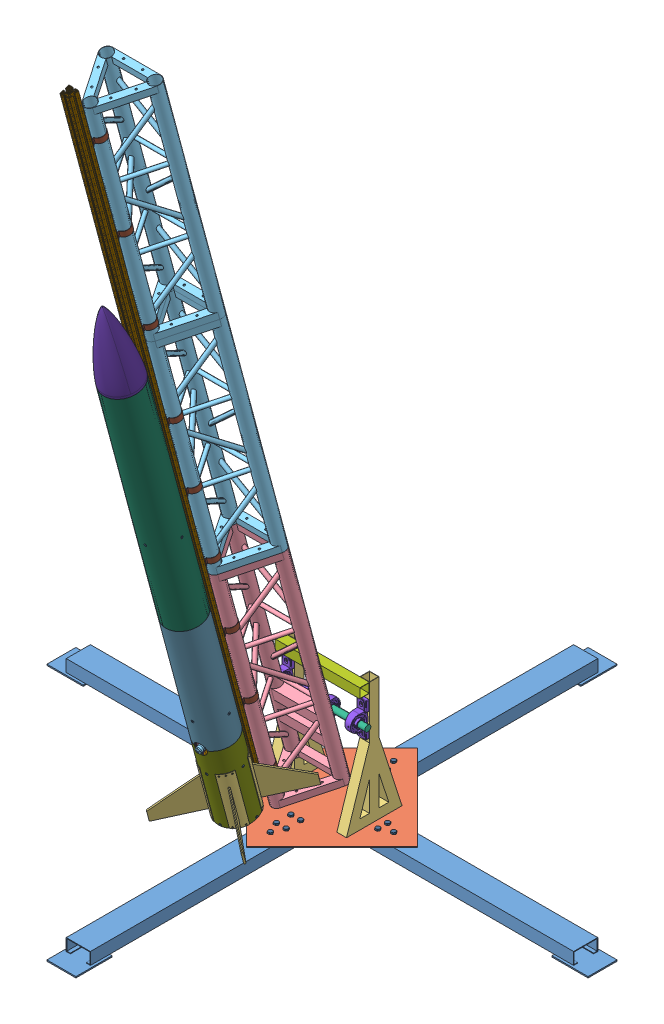
SolidWorks assembly Montagem_Diogo, configuration Default. Lengths in mm.
Overall size (2240 3135.17 2432.37).
172 component instances, 59 part files, 0 mates.
Components (placement in the parent):
- Pernas_Base_v2_Valor predeterminado-1: Pernas_Base_v2_Valor predeterminado [Default] at (-52.0403 -29.4954 1070) size (120 55 1070)
- Pernas_Base_v2_Valor predeterminado-2: Pernas_Base_v2_Valor predeterminado [Default] at (47.9597 -29.4954 1070) x (0 0 -1) z (1 0 0) size (120 55 1070)
- Pernas_Base_v2_Valor predeterminado-3: Pernas_Base_v2_Valor predeterminado [Default] at (-52.0403 -29.4954 970) x (0 0 1) z (-1 0 0) size (120 55 1070)
- Pernas_Base_v2_Valor predeterminado-4: Pernas_Base_v2_Valor predeterminado [Default] at (47.9597 -29.4954 970) x (-1 0 0) z (0 0 -1) size (120 55 1070)
- Base_v2_Valor predeterminado-1: Base_v2_Valor predeterminado [Default] at (280.8024 20.5046 1020) x (-0.707107 0 -0.707107) z (0 1 0) size (500 500 2.65)
- Haste_Valor predeterminado-1: Haste_Valor predeterminado [Default] at (172.9597 23.1546 1000) x (-1 0 0) z (0 0 -1) size (40 510 230)
- Haste_Valor predeterminado-2: Haste_Valor predeterminado [Default] at (-177.0403 23.1546 1040) size (40 510 230)
- Treliça-v3-mod-1: Treliça-v3-mod [Default] at (97.9597 162.3507 1076.7624) x (-0.5 0.224144 -0.836516) z (0.866025 0.12941 -0.482963) size (250.8 1000 224.01)
- Treliça-v2-mod-1: Treliça-v2-mod [Default] at (-2.0403 1083.4478 1502.8847) x (1 0 0) z (0 -0.258819 0.965926) size (250.8 1000 224.01)
- Treliça-v2-mod-2: Treliça-v2-mod [Default] at (-2.0403 2049.3736 1761.7038) x (1 0 0) z (0 -0.258819 0.965926) size (250.8 1000 224.01)
- Pino_1_pol_Valor predeterminado-1: Pino_1_pol_Valor predeterminado [Default] at (-197.3723 400.5345 1076.5) x (0 -0.908025 0.418916) z (1 0 0) size (25 25 400)
- Trava_Valor predeterminado-1: Trava_Valor predeterminado [Default] at (-177.0403 493.1546 1080) x (0 0 -1) z (1 0 0) size (40 40 350)
- ucp205-1: ucp205 [Default] at (152.9597 400.5345 1076.5) size (38.8 140 71.62)
- ucp205-2: ucp205 [Default] at (-157.0403 400.5345 1076.5) size (38.8 140 71.62)
- ucp205-3: ucp205 [Default] at (-48.0403 400.5345 1076.5) x (-1 0 0) z (0 0.258819 -0.965926) size (38.8 140 71.62)
- ucp205-4: ucp205 [Default] at (43.9597 400.5345 1076.5) x (-1 0 0) z (0 0.258819 -0.965926) size (38.8 140 71.62)
- perfil_40x40_Valor predeterminado_Como usinado_-1: perfil_40x40_Valor predeterminado_Como usinado_ [Default] at (-2.0403 1646.6109 1719.3533) x (1 0 0) z (0 -0.965926 -0.258819) size (40 40 3000)
- Parafuso_M_10_30mm_pols_91310A630-1: Parafuso_M_10_30mm_pols_91310A630 [Default] at (-2.0403 11.3546 1275) x (0 -1 0) z (0 0 1) size (36.4 19.63 17)
- Parafuso_M_10_30mm_pols_91310A630-2: Parafuso_M_10_30mm_pols_91310A630 [Default] at (-22.0403 11.3546 1170) x (0 -1 0) z (0 0 1) size (36.4 19.63 17)
- Parafuso_M_10_30mm_pols_91310A630-3: Parafuso_M_10_30mm_pols_91310A630 [Default] at (-22.0403 11.3546 1230) x (0 -1 0) z (0 0 1) size (36.4 19.63 17)
- Parafuso_M_10_30mm_pols_91310A630-4: Parafuso_M_10_30mm_pols_91310A630 [Default] at (17.9597 11.3546 1170) x (0 -1 0) z (0 0 1) size (36.4 19.63 17)
- Parafuso_M_10_30mm_pols_91310A630-5: Parafuso_M_10_30mm_pols_91310A630 [Default] at (17.9597 11.3546 1230) x (0 -1 0) z (-0.102079 0 0.994776) size (36.4 19.63 17)
- Parafuso_M_10_30mm_pols_91310A630-6: Parafuso_M_10_30mm_pols_91310A630 [Default] at (-2.0403 11.3546 765) x (0 -1 0) z (0 0 1) size (36.4 19.63 17)
- Parafuso_M_10_30mm_pols_91310A630-7: Parafuso_M_10_30mm_pols_91310A630 [Default] at (-22.0403 11.3546 870) x (0 -1 0) z (0 0 1) size (36.4 19.63 17)
- Parafuso_M_10_30mm_pols_91310A630-8: Parafuso_M_10_30mm_pols_91310A630 [Default] at (-22.0403 11.3546 810) x (0 -1 0) z (0 0 1) size (36.4 19.63 17)
- Parafuso_M_10_30mm_pols_91310A630-9: Parafuso_M_10_30mm_pols_91310A630 [Default] at (17.9597 11.3546 870) x (0 -1 0) z (0 0 1) size (36.4 19.63 17)
- Parafuso_M_10_30mm_pols_91310A630-10: Parafuso_M_10_30mm_pols_91310A630 [Default] at (17.9597 11.3546 810) x (0 -1 0) z (0.102079 0 0.994776) size (36.4 19.63 17)
- Parafuso_M_10_30mm_pols_91310A630-11: Parafuso_M_10_30mm_pols_91310A630 [Default] at (-257.0403 11.3546 1020) x (0 -1 0) z (-0.888061 0 0.459726) size (36.4 19.63 17)
- Parafuso_M_10_30mm_pols_91310A630-12: Parafuso_M_10_30mm_pols_91310A630 [Default] at (-212.0403 11.3546 1040) x (0 -1 0) z (-0.888061 0 0.459726) size (36.4 19.63 17)
- Parafuso_M_10_30mm_pols_91310A630-13: Parafuso_M_10_30mm_pols_91310A630 [Default] at (-212.0403 11.3546 1000) x (0 -1 0) z (-0.888061 0 0.459726) size (36.4 19.63 17)
- Parafuso_M_10_30mm_pols_91310A630-14: Parafuso_M_10_30mm_pols_91310A630 [Default] at (252.9597 11.3546 1020) x (0 -1 0) z (-0.888061 0 -0.459726) size (36.4 19.63 17)
- Parafuso_M_10_30mm_pols_91310A630-15: Parafuso_M_10_30mm_pols_91310A630 [Default] at (207.9597 11.3546 1040) x (0 -1 0) z (-0.888061 0 -0.459726) size (36.4 19.63 17)
- Parafuso_M_10_30mm_pols_91310A630-16: Parafuso_M_10_30mm_pols_91310A630 [Default] at (207.9597 11.3546 1000) x (0 -1 0) z (-0.888061 0 -0.459726) size (36.4 19.63 17)
- abraçadeira_2in-1: abraçadeira_2in [Default] at (-2.0403 251.1948 1324.7472) x (1 0 0) z (0 0.965926 0.258819) size (53.2 69.94 24)
- abraçadeira_2in-2: abraçadeira_2in [Default] at (-2.0403 540.9726 1402.3929) x (1 0 0) z (0 0.965926 0.258819) size (53.2 69.94 24)
- abraçadeira_2in-3: abraçadeira_2in [Default] at (-2.0403 830.7503 1480.0386) x (1 0 0) z (0 0.965926 0.258819) size (53.2 69.94 24)
- abraçadeira_2in-4: abraçadeira_2in [Default] at (-2.0403 1120.5281 1557.6843) x (1 0 0) z (0 0.965926 0.258819) size (53.2 69.94 24)
- abraçadeira_2in-5: abraçadeira_2in [Default] at (-2.0403 1410.3058 1635.33) x (1 0 0) z (0 0.965926 0.258819) size (53.2 69.94 24)
- abraçadeira_2in-6: abraçadeira_2in [Default] at (-2.0403 1700.0836 1712.9758) x (1 0 0) z (0 0.965926 0.258819) size (53.2 69.94 24)
- abraçadeira_2in-7: abraçadeira_2in [Default] at (-2.0403 2086.4539 1816.5034) x (1 0 0) z (0 0.965926 0.258819) size (53.2 69.94 24)
- abraçadeira_2in-8: abraçadeira_2in [Default] at (-2.0403 2472.8242 1920.031) x (1 0 0) z (0 0.965926 0.258819) size (53.2 69.94 24)
- abraçadeira_2in-9: abraçadeira_2in [Default] at (-2.0403 2859.1945 2023.5586) x (1 0 0) z (0 0.965926 0.258819) size (53.2 69.94 24)
- porca_martelo_M6-1: porca_martelo_M6 [Default] at (-2.0403 2868.5857 2034.8748) x (0 0.965926 0.258819) z (-1 0 0) size (7.7 6 16)
- DDLS_II_v05_LASC_Valor predeterminado-1: DDLS_II_v05_LASC_Valor predeterminado [Default] at (8.8764 189.1016 1425.0956) x (-0.773658 0.163989 -0.612014) z (0.633604 0.200237 -0.747296) size (514 2164.68 514)
  - fuselagem_v04_Valor predeterminado-1: fuselagem_v04_Valor predeterminado [Default] x (-0.707107 0 -0.707107) z (0.707107 0 -0.707107) size (210.6 2155.68 210.6)
    - pescoco_valvula_26102020_1025_Valor predeterminado-1: pescoco_valvula_26102020_1025_Valor predeterminado [Default] at (0 330 0) size (145.71 150 150)
    - tubo2_17022020_1025_Valor predeterminado-1: tubo2_17022020_1025_Valor predeterminado [Default] at (0 330 0) size (155 514.53 155)
    - tubo3_17022020_1025_Valor predeterminado-1: tubo3_17022020_1025_Valor predeterminado [Default] at (0 843 0) size (155 1044.68 155)
    - tubo1_17022020_1025_Valor predeterminado-1: tubo1_17022020_1025_Valor predeterminado [Default] at origin size (155 331.53 155)
    - DDLSII_Coifa_VonKarman_v1_Valor predeterminado-1: DDLSII_Coifa_VonKarman_v1_Valor predeterminado [Default] at (0 2155.68 0) x (0 -1 0) z (0.503622 0 -0.863924) size (468 154 154)
  - DIN 912 - M6 x 1 x 25_Valor predeterminado-1: DIN 912 - M6 x 1 x 25_Valor predeterminado [Default] at (74.3 6 0) x (-1 0 0) z (0 0.043133 -0.999069) size (31 10 10)
  - DIN 7991 - M5 x 0.8 x 10_Valor predeterminado-1: DIN 7991 - M5 x 0.8 x 10_Valor predeterminado [Default] at (-54.9873 6 54.9873) x (0.707107 0 -0.707107) z (0.691467 0.209156 0.691467) size (10 9.64 9.64)
  - DIN 912 - M5 x 0.8 x 10_Valor predeterminado-1: DIN 912 - M5 x 0.8 x 10_Valor predeterminado [Default] at (0 818 -73.3) x (0 0 1) z (-0.394606 -0.918851 0) size (15 8.5 8.5)
  - DIN 912 - M5 x 0.8 x 10_Valor predeterminado-2: DIN 912 - M5 x 0.8 x 10_Valor predeterminado [Default] at (-73.3 818 0) x (1 0 0) z (0 -0.98779 -0.155794) size (15 8.5 8.5)
  - DIN 912 - M6 x 1 x 25_Valor predeterminado-2: DIN 912 - M6 x 1 x 25_Valor predeterminado [Default] at (0 223 74.3) x (0 0 -1) z (0.737606 0.675231 0) size (31 10 10)
  - DIN 912 - M6 x 1 x 25_Valor predeterminado-3: DIN 912 - M6 x 1 x 25_Valor predeterminado [Default] at (-74.3 223 0) x (1 0 0) z (0 -0.737606 0.675231) size (31 10 10)
  - DDLSII_Aleta_Trapeizodal_v1_Valor predeterminado-1: DDLSII_Aleta_Trapeizodal_v1_Valor predeterminado [Default] at (0 26.4771 77) x (0 1 0) z (0 0 1) size (231.48 60.46 185.86)
  - DIN 912 - M6 x 1 x 25_Valor predeterminado-4: DIN 912 - M6 x 1 x 25_Valor predeterminado [Default] at (0 6 -74.3) x (0 0 1) z (-0.999069 0.043133 0) size (31 10 10)
  - DIN 912 - M6 x 1 x 25_Valor predeterminado-5: DIN 912 - M6 x 1 x 25_Valor predeterminado [Default] at (0 6 74.3) x (0 0 -1) z (0.924066 0.382233 0) size (31 10 10)
  - DDLSII_Aleta_Trapeizodal_v1_Valor predeterminado-2: DDLSII_Aleta_Trapeizodal_v1_Valor predeterminado [Default] at (-77 26.4771 0) x (0 1 0) z (-1 0 0) size (231.48 60.46 185.86)
  - DIN 912 - M6 x 1 x 25_Valor predeterminado-6: DIN 912 - M6 x 1 x 25_Valor predeterminado [Default] at (74.3 223 0) x (-1 0 0) z (0 0.200992 -0.979593) size (31 10 10)
  - DIN 912 - M5 x 0.8 x 10_Valor predeterminado-3: DIN 912 - M5 x 0.8 x 10_Valor predeterminado [Default] at (73.3 448 0) x (-1 0 0) z (0 0.09878 0.995109) size (15 8.5 8.5)
  - DIN 912 - M5 x 0.8 x 10_Valor predeterminado-4: DIN 912 - M5 x 0.8 x 10_Valor predeterminado [Default] at (0 818 73.3) x (0 0 -1) z (-0.728474 -0.685073 0) size (15 8.5 8.5)
  - DIN 912 - M5 x 0.8 x 10_Valor predeterminado-5: DIN 912 - M5 x 0.8 x 10_Valor predeterminado [Default] at (73.3 818 0) x (-1 0 0) z (0 -0.918851 -0.394606) size (15 8.5 8.5)
  - DIN 912 - M6 x 1 x 25_Valor predeterminado-7: DIN 912 - M6 x 1 x 25_Valor predeterminado [Default] at (-74.3 6 0) x (1 0 0) z (0 -0.843653 0.536889) size (31 10 10)
  - DIN 912 - M5 x 0.8 x 10_Valor predeterminado-6: DIN 912 - M5 x 0.8 x 10_Valor predeterminado [Default] at (-73.3 448 0) x (1 0 0) z (0 0.968882 -0.247524) size (15 8.5 8.5)
  - DIN 912 - M5 x 0.8 x 10_Valor predeterminado-7: DIN 912 - M5 x 0.8 x 10_Valor predeterminado [Default] at (0 448 -73.3) x (0 0 1) z (0.995109 0.09878 0) size (15 8.5 8.5)
  - DIN 7991 - M5 x 0.8 x 10_Valor predeterminado-2: DIN 7991 - M5 x 0.8 x 10_Valor predeterminado [Default] at (54.9873 6 54.9873) x (-0.707107 0 -0.707107) z (0.461185 -0.758034 -0.461185) size (10 9.64 9.64)
  - DIN 912 - M5 x 0.8 x 10_Valor predeterminado-8: DIN 912 - M5 x 0.8 x 10_Valor predeterminado [Default] at (0 448 73.3) x (0 0 -1) z (-0.968882 -0.247524 0) size (15 8.5 8.5)
  - DIN 7991 - M5 x 0.8 x 10_Valor predeterminado-3: DIN 7991 - M5 x 0.8 x 10_Valor predeterminado [Default] at (54.9873 223 54.9873) x (-0.707107 0 -0.707107) z (0.569024 -0.593652 -0.569024) size (10 9.64 9.64)
  - DDLSII_Aleta_Trapeizodal_v1_Valor predeterminado-3: DDLSII_Aleta_Trapeizodal_v1_Valor predeterminado [Default] at (77 26.4771 0) x (0 1 0) z (1 0 0) size (231.48 60.46 185.86)
  - DIN 7991 - M5 x 0.8 x 10_Valor predeterminado-4: DIN 7991 - M5 x 0.8 x 10_Valor predeterminado [Default] at (54.9873 448 54.9873) x (-0.707107 0 -0.707107) z (0.634453 -0.441518 -0.634453) size (10 9.64 9.64)
  - DIN 7991 - M5 x 0.8 x 10_Valor predeterminado-5: DIN 7991 - M5 x 0.8 x 10_Valor predeterminado [Default] at (54.9873 1204 54.9873) x (-0.707107 0 -0.707107) z (0.669219 -0.322942 -0.669219) size (10 9.64 9.64)
  - DIN 912 - M6 x 1 x 25_Valor predeterminado-8: DIN 912 - M6 x 1 x 25_Valor predeterminado [Default] at (0 223 -74.3) x (0 0 1) z (-0.999069 0.043133 0) size (31 10 10)
  - Paraquedas_Valor predeterminado-1: Paraquedas_Valor predeterminado [Default] at (0 1268.1902 0) x (-0.508851 0 0.860854) z (-0.860854 0 -0.508851) size (142 500 142)
  - DIN 7991 - M5 x 0.8 x 20_Valor predeterminado-1: DIN 7991 - M5 x 0.8 x 20_Valor predeterminado [Default] at (-30 1189.5 -51.9615) x (0 1 0) z (-0.631711 0 -0.775204) size (20 9.64 9.64)
  - DIN 7991 - M5 x 0.8 x 20_Valor predeterminado-2: DIN 7991 - M5 x 0.8 x 20_Valor predeterminado [Default] at (51.9615 1189.5 -30) x (0 1 0) z (-0.227827 0 -0.973702) size (20 9.64 9.64)
  - 90592A022_STEEL HEX NUT_90592A022-1: 90592A022_STEEL HEX NUT_90592A022 [Default] at (0 1857.73 0) size (13 6.97 15.01)
  - DIN 7991 - M5 x 0.8 x 10_Valor predeterminado-6: DIN 7991 - M5 x 0.8 x 10_Valor predeterminado [Default] at (54.9873 6 -54.9873) x (-0.707107 0 0.707107) z (-0.265712 -0.926712 -0.265712) size (10 9.64 9.64)
  - DIN 7991 - M5 x 0.8 x 10_Valor predeterminado-7: DIN 7991 - M5 x 0.8 x 10_Valor predeterminado [Default] at (54.9873 223 -54.9873) x (-0.707107 0 0.707107) z (-0.223229 -0.948861 -0.223229) size (10 9.64 9.64)
  - DIN 7991 - M5 x 0.8 x 20_Valor predeterminado-3: DIN 7991 - M5 x 0.8 x 20_Valor predeterminado [Default] at (30 1189.5 51.9615) x (0 1 0) z (-0.040246 0 -0.99919) size (20 9.64 9.64)
  - DIN 7991 - M5 x 0.8 x 10_Valor predeterminado-8: DIN 7991 - M5 x 0.8 x 10_Valor predeterminado [Default] at (-54.9873 1204 -54.9873) x (0.707107 0 0.707107) z (-0.461185 -0.758034 0.461185) size (10 9.64 9.64)
  - Assembly_Completo_LASC_sem_antiretorno_Valor predeterminado-1: Assembly_Completo_LASC_sem_antiretorno_Valor predeterminado [Default] at (-564.4867 231.8653 423.7249) x (0 -1 0) z (0.707107 0 -0.707107) size (872.4 212.33 212.33)
    - Assembly_Motor_8_1_Valor predeterminado-1: Assembly_Motor_8_1_Valor predeterminado [Default] at (5.6555 -208.983 804.3704) x (0 0.699248 0.714879) z (0 0.714879 -0.699248) size (150.15 268 150.15)
      - Parafuso M6_Valor predeterminado-1: Parafuso M6_Valor predeterminado [Default] at (29.0923 3.2098 201.9329) x (-0.871499 0 0.490397) z (-0.490397 0 -0.871499) size (8 8 20.2)
      - Casing (1)_Valor predeterminado-1: Casing (1)_Valor predeterminado [Default] at (1.0416 -11.7902 152.0832) x (0.999902 0 0.014033) z (-0.014033 0 0.999902) size (114.4 247 114.4)
      - Parafuso M6_Valor predeterminado-2: Parafuso M6_Valor predeterminado [Default] at (-27.0091 3.2098 102.2334) x (0.871499 0 -0.490397) z (0.490397 0 0.871499) size (8 8 20.2)
      - Parafuso M6_Valor predeterminado-3: Parafuso M6_Valor predeterminado [Default] at (-48.8082 220.2098 180.1339) x (-0.490397 0 -0.871499) z (0.871499 0 -0.490397) size (8 8 20.2)
      - Parafuso M6_Valor predeterminado-4: Parafuso M6_Valor predeterminado [Default] at (50.8913 3.2098 124.0324) x (0.490397 0 0.871499) z (-0.871499 0 0.490397) size (8 8 20.2)
      - Parafuso M6_Valor predeterminado-5: Parafuso M6_Valor predeterminado [Default] at (-48.8082 3.2098 180.1339) x (-0.490397 0 -0.871499) z (0.871499 0 -0.490397) size (8 8 20.2)
      - Parafuso M6_Valor predeterminado-6: Parafuso M6_Valor predeterminado [Default] at (29.0923 220.2098 201.9329) x (-0.871499 0 0.490397) z (-0.490397 0 -0.871499) size (8 8 20.2)
      - Parafuso M6_Valor predeterminado-7: Parafuso M6_Valor predeterminado [Default] at (30.1874 3.2098 102.8657) x (0.860446 0 0.509542) z (-0.509542 0 0.860446) size (8 8 20.2)
      - Parafuso M6_Valor predeterminado-8: Parafuso M6_Valor predeterminado [Default] at (50.2591 3.2098 181.2289) x (-0.509542 0 0.860446) z (-0.860446 0 -0.509542) size (8 8 20.2)
      - Parafuso M6_Valor predeterminado-9: Parafuso M6_Valor predeterminado [Default] at (-48.8082 220.2098 180.1339) x (-0.490397 0 -0.871499) z (0.871499 0 -0.490397) size (8 8 20.2)
      - Parafuso M6_Valor predeterminado-10: Parafuso M6_Valor predeterminado [Default] at (30.1874 3.2098 102.8657) x (0.860446 0 0.509542) z (-0.509542 0 0.860446) size (8 8 20.2)
      - Parafuso M6_Valor predeterminado-11: Parafuso M6_Valor predeterminado [Default] at (50.8913 3.2098 124.0324) x (0.490397 0 0.871499) z (-0.871499 0 0.490397) size (8 8 20.2)
      - Parafuso M6_Valor predeterminado-12: Parafuso M6_Valor predeterminado [Default] at (-48.1759 3.2098 122.9374) x (0.509542 0 -0.860446) z (0.860446 0 0.509542) size (8 8 20.2)
      - Parafuso M6_Valor predeterminado-13: Parafuso M6_Valor predeterminado [Default] at (-48.1759 3.2098 122.9374) x (0.509542 0 -0.860446) z (0.860446 0 0.509542) size (8 8 20.2)
      - Parafuso M6_Valor predeterminado-14: Parafuso M6_Valor predeterminado [Default] at (29.0923 3.2098 201.9329) x (-0.871499 0 0.490397) z (-0.490397 0 -0.871499) size (8 8 20.2)
      - Parafuso M6_Valor predeterminado-15: Parafuso M6_Valor predeterminado [Default] at (-27.0091 3.2098 102.2334) x (0.871499 0 -0.490397) z (0.490397 0 0.871499) size (8 8 20.2)
      - Parafuso M6_Valor predeterminado-16: Parafuso M6_Valor predeterminado [Default] at (-27.0091 220.2098 102.2334) x (0.871499 0 -0.490397) z (0.490397 0 0.871499) size (8 8 20.2)
      - Parafuso M6_Valor predeterminado-17: Parafuso M6_Valor predeterminado [Default] at (50.2591 220.2098 181.2289) x (-0.509542 0 0.860446) z (-0.860446 0 -0.509542) size (8 8 20.2)
      - Parafuso M6_Valor predeterminado-18: Parafuso M6_Valor predeterminado [Default] at (50.8913 220.2098 124.0324) x (0.490397 0 0.871499) z (-0.871499 0 0.490397) size (8 8 20.2)
      - Parafuso M6_Valor predeterminado-19: Parafuso M6_Valor predeterminado [Default] at (-48.1759 220.2098 122.9374) x (0.509542 0 -0.860446) z (0.860446 0 0.509542) size (8 8 20.2)
      - Parafuso M6_Valor predeterminado-20: Parafuso M6_Valor predeterminado [Default] at (-28.1042 3.2098 201.3007) x (-0.860446 0 -0.509542) z (0.509542 0 -0.860446) size (8 8 20.2)
      - Parafuso M6_Valor predeterminado-21: Parafuso M6_Valor predeterminado [Default] at (-48.8082 3.2098 180.1339) x (-0.490397 0 -0.871499) z (0.871499 0 -0.490397) size (8 8 20.2)
      - Parafuso M6_Valor predeterminado-22: Parafuso M6_Valor predeterminado [Default] at (50.2591 3.2098 181.2289) x (-0.509542 0 0.860446) z (-0.860446 0 -0.509542) size (8 8 20.2)
      - Parafuso M6_Valor predeterminado-23: Parafuso M6_Valor predeterminado [Default] at (29.0923 220.2098 201.9329) x (-0.871499 0 0.490397) z (-0.490397 0 -0.871499) size (8 8 20.2)
      - Parafuso M6_Valor predeterminado-24: Parafuso M6_Valor predeterminado [Default] at (-28.1042 3.2098 201.3007) x (-0.860446 0 -0.509542) z (0.509542 0 -0.860446) size (8 8 20.2)
      - injetor_Valor predeterminado-1: injetor_Valor predeterminado [Default] at (1.0416 8.2098 152.0832) x (-0.860446 0 -0.509542) z (-0.509542 0 0.860446) size (109.6 43 109.6)
      - Parafuso M6_Valor predeterminado-25: Parafuso M6_Valor predeterminado [Default] at (-27.0091 220.2098 102.2334) x (0.871499 0 -0.490397) z (0.490397 0 0.871499) size (8 8 20.2)
      - Parafuso M6_Valor predeterminado-26: Parafuso M6_Valor predeterminado [Default] at (30.1874 220.2098 102.8657) x (0.860446 0 0.509542) z (-0.509542 0 0.860446) size (8 8 20.2)
      - Parafuso M6_Valor predeterminado-27: Parafuso M6_Valor predeterminado [Default] at (-48.1759 220.2098 122.9374) x (0.509542 0 -0.860446) z (0.860446 0 0.509542) size (8 8 20.2)
      - placa_injetora_Valor predeterminado-1: placa_injetora_Valor predeterminado [Default] at (1.0416 8.2098 152.0832) x (-0.860446 0 -0.509542) z (0 -1 0) size (90 90 12)
      - Grao_DDLS_2_Peca_Modificada_8_1_Valor predeterminado-1: Grao_DDLS_2_Peca_Modificada_8_1_Valor predeterminado [Default] at (1.0416 135.1998 152.0832) x (-0.535831 0 -0.844325) z (0 -1 0) size (101.6 101.6 70.19)
      - Montagem_Tubeira_Coupler_8_1_2020_Valor predeterminado-1: Montagem_Tubeira_Coupler_8_1_2020_Valor predeterminado [Default] at (-6.5392 197.5822 154.1075) x (-0.966147 0 0.257991) z (0.257991 0 0.966147) size (109.6 65 109.6)
        - Coupler_DDLS_2_Peca_Modificada_8_1_Valor predeterminado-1: Coupler_DDLS_2_Peca_Modificada_8_1_Valor predeterminado [Default] at (-7.8464 -7.1276 0) size (109.6 65 109.6)
        - Tubeira_DDLS_2_Peca_Modificada_8_1_Valor predeterminado-1: Tubeira_DDLS_2_Peca_Modificada_8_1_Valor predeterminado [Default] at (-7.8464 4.2977 0) size (93.6 65 93.6)
      - Parafuso M6_Valor predeterminado-28: Parafuso M6_Valor predeterminado [Default] at (50.2591 220.2098 181.2289) x (-0.509542 0 0.860446) z (-0.860446 0 -0.509542) size (8 8 20.2)
      - Parafuso M6_Valor predeterminado-29: Parafuso M6_Valor predeterminado [Default] at (-28.1042 220.2098 201.3007) x (-0.860446 0 -0.509542) z (0.509542 0 -0.860446) size (8 8 20.2)
      - Parafuso M6_Valor predeterminado-30: Parafuso M6_Valor predeterminado [Default] at (30.1874 220.2098 102.8657) x (0.860446 0 0.509542) z (-0.509542 0 0.860446) size (8 8 20.2)
      - Parafuso M6_Valor predeterminado-31: Parafuso M6_Valor predeterminado [Default] at (50.8913 220.2098 124.0324) x (0.490397 0 0.871499) z (-0.871499 0 0.490397) size (8 8 20.2)
      - Parafuso M6_Valor predeterminado-32: Parafuso M6_Valor predeterminado [Default] at (-28.1042 220.2098 201.3007) x (-0.860446 0 -0.509542) z (0.509542 0 -0.860446) size (8 8 20.2)
    - T-1.2_3.4_1.2_NPT_MACHO_Valor predeterminado-1: T-1.2_3.4_1.2_NPT_MACHO_Valor predeterminado [Default] at (-98.5347 -99.5336 698.7712) x (0 0 1) z (-1 0 0) size (26.12 57 82)
    - Montagem_Tanque_Completo_Valor predeterminado-1: Montagem_Tanque_Completo_Valor predeterminado [Default] at (-384.0347 -108.7807 655.6336) x (0 -0.209601 -0.977787) z (0 0.977787 -0.209601) size (132.5 465 132.5)
      - TampaInferior_Valor predeterminado-1: TampaInferior_Valor predeterminado [Default] at (-44.1176 -202.8436 0) x (-0.999998 0 -0.002101) z (-0.002101 0 0.999998) size (100 46 100)
      - Tubo_Valor predeterminado-1: Tubo_Valor predeterminado [Default] at (-44.1176 -207.5 0) size (111.1 455 111.1)
      - TampaSuperior_Valor predeterminado-1: TampaSuperior_Valor predeterminado [Default] at (-44.1176 242.8436 0) x (0.415415 0 -0.909632) z (0.909632 0 0.415415) size (100 36 100)
    - Assembly_Conexões_Valor predeterminado-1: Assembly_Conexões_Valor predeterminado [Default] at (-139.5347 -113.07 687.6612) size (476.1 35.34 86.53)
      - valve_solenoide_Valor predeterminado-1: valve_solenoide_Valor predeterminado [Default] at (-28.8974 13.5364 68.8576) x (0 -0.833828 0.552025) z (1 0 0) size (25.5 25.5 61)
      - Montagem1_Valor predeterminado-1: Montagem1_Valor predeterminado [Default] at (-88.5249 15.3016 11.6109) x (0 -1 0) z (1 0 0) size (25.66 57.22 444)
        - connection_Valor predeterminado-1: connection_Valor predeterminado [Default] at (1.7652 0.5009 44.5249) size (25.66 22.22 44.5)
        - tuboexterno_Valor predeterminado-1: tuboexterno_Valor predeterminado [Default] at (1.7652 -45.6091 66.5249) x (1 0 0) z (0 1 0) size (3.17 3.17 35)
        - tubointerno_Valor predeterminado-1: tubointerno_Valor predeterminado [Default] at (1.7652 -4.4991 -355.4751) x (0.916717 -0.399536 0) z (0 0 1) size (3.17 3.17 400)
    - _______ ____ _-_ (__15)_00-1: _______ ____ _-_ (__15)_00 [Default] at (-43.3347 -99.5336 698.7712) x (-1 0 0) z (0 -0.993956 0.109781) size (55.8 47.55 29)
    - Engate-1.2-NPT_Valor predeterminado-1: Engate-1.2-NPT_Valor predeterminado [Default] at (-98.5347 -57.5336 698.7712) x (0.506726 0 0.862107) z (0 1 0) size (31.18 27 50)
  - DIN 7991 - M5 x 0.8 x 10_Valor predeterminado-9: DIN 7991 - M5 x 0.8 x 10_Valor predeterminado [Default] at (-54.9873 223 54.9873) x (0.707107 0 -0.707107) z (0.606425 0.514294 0.606425) size (10 9.64 9.64)
  - DIN 7991 - M5 x 0.8 x 10_Valor predeterminado-10: DIN 7991 - M5 x 0.8 x 10_Valor predeterminado [Default] at (-54.9873 1204 54.9873) x (0.707107 0 -0.707107) z (0.168235 0.971285 0.168235) size (10 9.64 9.64)
  - DIN 7991 - M5 x 0.8 x 10_Valor predeterminado-11: DIN 7991 - M5 x 0.8 x 10_Valor predeterminado [Default] at (-54.9873 223 -54.9873) x (0.707107 0 0.707107) z (-0.461185 -0.758034 0.461185) size (10 9.64 9.64)
  - DIN 7991 - M5 x 0.8 x 10_Valor predeterminado-12: DIN 7991 - M5 x 0.8 x 10_Valor predeterminado [Default] at (-54.9873 448 54.9873) x (0.707107 0 -0.707107) z (0.432945 0.790644 0.432945) size (10 9.64 9.64)
  - DIN 7991 - M5 x 0.8 x 10_Valor predeterminado-13: DIN 7991 - M5 x 0.8 x 10_Valor predeterminado [Default] at (-54.9873 448 -54.9873) x (0.707107 0 0.707107) z (-0.461185 -0.758034 0.461185) size (10 9.64 9.64)
  - 98689A116_ METRIC GENERAL PURPOSE WASHERS_98689A116-1: 98689A116_ METRIC GENERAL PURPOSE WASHERS_98689A116 [Default] at (0 1854.48 0) x (1 0 0) z (0 -1 0) size (15 15 1.8)
  - DIN 7991 - M5 x 0.8 x 10_Valor predeterminado-14: DIN 7991 - M5 x 0.8 x 10_Valor predeterminado [Default] at (54.9873 1204 -54.9873) x (-0.707107 0 0.707107) z (-0.214218 -0.953007 -0.214218) size (10 9.64 9.64)
  - 4843T140_GALVANIZED STEEL EYEBOLT - FOR LIFTING_4843T14-1: 4843T140_GALVANIZED STEEL EYEBOLT - FOR LIFTING_4843T14 [Default] at (0 1837.68 0) x (-0.528714 0 0.8488) z (0.8488 0 0.528714) size (47 92.13 22)
  - DIN 7991 - M5 x 0.8 x 10_Valor predeterminado-15: DIN 7991 - M5 x 0.8 x 10_Valor predeterminado [Default] at (-54.9873 6 -54.9873) x (0.707107 0 0.707107) z (-0.461185 -0.758034 0.461185) size (10 9.64 9.64)
  - DIN 7991 - M5 x 0.8 x 20_Valor predeterminado-4: DIN 7991 - M5 x 0.8 x 20_Valor predeterminado [Default] at (-51.9615 1189.5 30) x (0 1 0) z (-0.432374 0 -0.901694) size (20 9.64 9.64)
  - DIN 7991 - M5 x 0.8 x 10_Valor predeterminado-16: DIN 7991 - M5 x 0.8 x 10_Valor predeterminado [Default] at (54.9873 448 -54.9873) x (-0.707107 0 0.707107) z (-0.20409 -0.957442 -0.20409) size (10 9.64 9.64)
  - bk_coifa_v3_26102020_2137_Valor predeterminado-1: bk_coifa_v3_26102020_2137_Valor predeterminado [Default] at (0 1845.18 0) size (146 15 146)
  - bk_tanque_conexão_24022020_1714_Valor predeterminado-1: bk_tanque_conexão_24022020_1714_Valor predeterminado [Default] at (0 813 0) size (149.46 10 149.46)
  - bk_motor_V2_16022020_2057_Valor predeterminado-1: bk_motor_V2_16022020_2057_Valor predeterminado [Default] at origin size (149.46 12 149.46)
  - longarina_v2_19032020_1534_Valor predeterminado-1: longarina_v2_19032020_1534_Valor predeterminado [Default] at (0 600 66.7125) x (-1 0 0) z (0 0 -1) size (12.7 1200 3.17)
  - bk_tanque_v2_17022020_1034_Valor predeterminado-1: bk_tanque_v2_17022020_1034_Valor predeterminado [Default] at (0 443 0) size (149.46 10 149.46)
  - bk_recuperacao_v3_b__06042020_1104_Valor predeterminado-1: bk_recuperacao_v3_b__06042020_1104_Valor predeterminado [Default] at (0 1200 0) size (150 12 150)
  - longarina_v2_19032020_1534_Valor predeterminado-2: longarina_v2_19032020_1534_Valor predeterminado [Default] at (-66.7125 600 0) x (0 0 1) z (-1 0 0) size (12.7 1200 3.17)
  - longarina_v2_19032020_1534_Valor predeterminado-3: longarina_v2_19032020_1534_Valor predeterminado [Default] at (0 600 -66.7125) x (-1 0 0) z (0 0 -1) size (12.7 1200 3.17)
  - longarina_v2_19032020_1534_Valor predeterminado-4: longarina_v2_19032020_1534_Valor predeterminado [Default] at (66.7125 600 0) x (0 0 -1) z (1 0 0) size (12.7 1200 3.17)
  - bk_motor_V2_16022020_2057_Valor predeterminado-2: bk_motor_V2_16022020_2057_Valor predeterminado [Default] at (0 217 0) size (149.46 12 149.46)
  - bk_tanque_conexaov2_24022020_1910 - Copia_Valor predeterminado-1: bk_tanque_conexaov2_24022020_1910 - Copia_Valor predeterminado [Default] at (0 808 0) size (149.46 20 149.46)
  - bk_tanque_conexão_24022020_1714_Valor predeterminado-2: bk_tanque_conexão_24022020_1714_Valor predeterminado [Default] at (0 803 0) size (149.46 10 149.46)
  - payload_Valor predeterminado-1: payload_Valor predeterminado [Default] at (0 1233 35.309) size (50 50 50)
  - canister_Valor predeterminado-1: canister_Valor predeterminado [Default] at (20 1208 -40.8627) size (25 40 25)
  - bk_tanque_superior_v03_Valor predeterminado-1: bk_tanque_superior_v03_Valor predeterminado [Default] at (0 813 0) size (145.45 10 145.45)
  - bk_eletronica_inferior_v3_06042020_1056_Valor predeterminado-1: bk_eletronica_inferior_v3_06042020_1056_Valor predeterminado [Default] at (0 880 0) x (0 0 1) z (-1 0 0) size (129.7 10 129.7)
  - chapa_eletronica_v3_06042020_2311_Valor predeterminado-1: chapa_eletronica_v3_06042020_2311_Valor predeterminado [Default] at (0 1040 0) x (-0.707107 0 0.707107) z (-0.707107 0 -0.707107) size (120 300 10)
  - o-ring_150_2_Valor predeterminado-1: o-ring_150_2_Valor predeterminado [Default] at (0 1209 0) size (152 2 152)
  - u_bolt_v1_17022020_1149_Valor predeterminado-1: u_bolt_v1_17022020_1149_Valor predeterminado [Default] at (0 1191.1656 0) size (50.67 63.34 9.53)
  - bk_eletronica_superior_v3_06042020_1056_Valor predeterminado-1: bk_eletronica_superior_v3_06042020_1056_Valor predeterminado [Default] at (0 1190 0) x (0 0 1) z (-1 0 0) size (129.7 10 129.7)
  - 95462A515_GRADE 5 STEEL HEX NUT_95462A515-1: 95462A515_GRADE 5 STEEL HEX NUT_95462A515 [Default] at (-20.575 1212.1672 0) x (-0.588996 0 -0.808136) z (0 -1 0) size (14.29 16.5 8.89)
  - 95462A515_GRADE 5 STEEL HEX NUT_95462A515-2: 95462A515_GRADE 5 STEEL HEX NUT_95462A515 [Default] at (-20.575 1195.8328 0) x (-0.939128 0 -0.343567) z (0 -1 0) size (14.29 16.5 8.89)
  - 95462A515_GRADE 5 STEEL HEX NUT_95462A515-3: 95462A515_GRADE 5 STEEL HEX NUT_95462A515 [Default] at (20.575 1195.8328 0) x (-0.934117 0 -0.356968) z (0 1 0) size (14.29 16.5 8.89)
  - DDLSII_Aleta_Trapeizodal_v1_Valor predeterminado-4: DDLSII_Aleta_Trapeizodal_v1_Valor predeterminado [Default] at (0 26.4771 -77) x (0 1 0) z (0 0 -1) size (231.48 60.46 185.86)
  - 95462A515_GRADE 5 STEEL HEX NUT_95462A515-4: 95462A515_GRADE 5 STEEL HEX NUT_95462A515 [Default] at (20.575 1212.1672 0) x (-0.605573 0 -0.795789) z (0 1 0) size (14.29 16.5 8.89)
